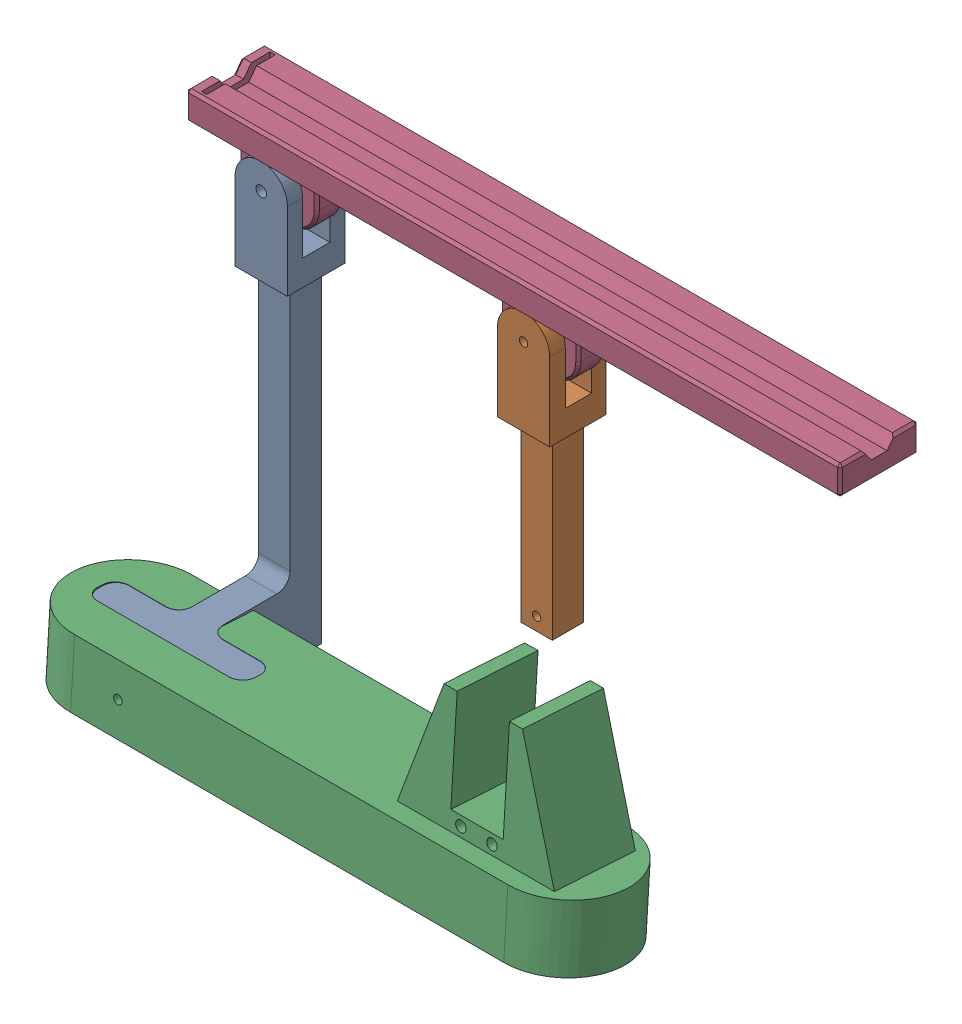
SolidWorks assembly assemble, configuration Default. Lengths in mm.
Overall size (264.89 179.68 81.84).
4 component instances, 4 part files, 7 mates.
Components (placement in the parent):
- support-1: support [預設] at (-19.938 79.6942 -11.8669) size (60 165.28 59.5)
- link-1: link [預設] at (80.062 79.6942 -12.1469) size (20 108.28 22)
- base-1: base [預設] at (-19.938 76.5922 -23.999) x (1 0 0) z (0 0.063111 0.998006) size (210.78 70 45.16)
- platform-1: platform [預設] at (205.062 92.1942 -21.1069) x (-1 0 0) z (0 1 0) size (250 30 36)
Mates (geometry in assembly coordinates):
- 平行1: parallel aligned: line of support-1 through (-44.938 -50.5822 42.6331) axis (1 0 0); line of base-1 through (-44.938 -49.7325 42.6063) axis (1 0 0)
- 重合/共線/共點4: coincident: point of support-1; unknown of base-1
- 平行3: parallel: plane of support-1 through (10.062 -50.5822 0.1331) normal (0 1 0); line of base-1 through (-49.938 -62.2076 43.3952) axis (1 0 0)
- 同軸心1: concentric anti-aligned: cylinder of support-1 through (-19.938 79.6942 0.1331) axis (0 0 -1) radius 1.985; circle of platform-1
- 重合/共線/共點5: coincident anti-aligned: plane of support-1 through (156.062 79.6942 -11.1069) normal (0 0 1); plane of platform-1 through (205.062 67.1942 -11.1069) normal (0 0 -1)
- 重合/共線/共點6: coincident aligned: circle of link-1; circle of platform-1
- 平行4: parallel anti-aligned: plane of link-1 through (90.062 79.6942 -11.1869) normal (0 0 1); plane of platform-1 through (205.062 67.1942 -11.1069) normal (0 0 -1)
